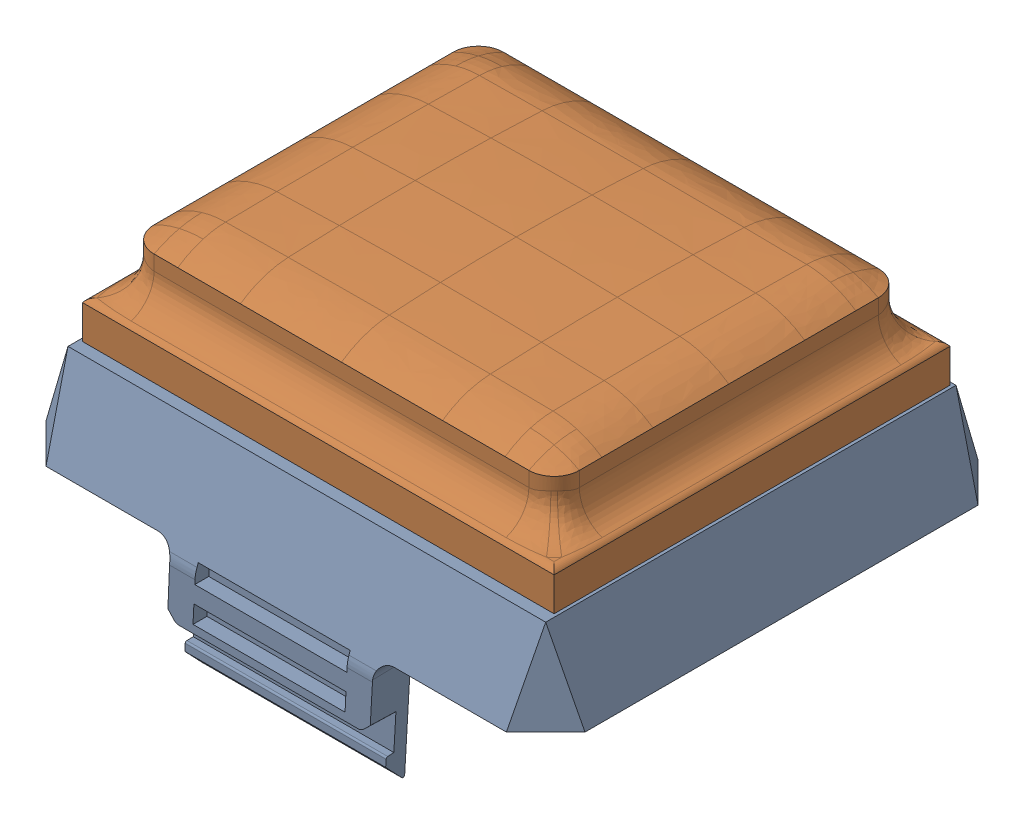
SolidWorks assembly ContiALL2, configuration 默认. Lengths in mm.
Overall size (32 17.53 28.9).
7 component instances, 7 part files, 18 mates.
Components (placement in the parent):
- 3Con1612611Support-1: 3Con1612611Support [默认] at origin size (32 12.05 28.9)
- 3Con1612611OriginalSkin_TOP-1: 3Con1612611OriginalSkin_TOP [默认] at (0 2 0) size (28.02 6.25 23.52) (hidden)
- 3Con1612611Lens-1: 3Con1612611Lens [默认] at (-1.1243 18 1.5226) x (1 0 0) z (0 -1 0) size (24.45 17.04 1)
- 3Con1612611UP-2: 3Con1612611UP [默认] at (0 2 0) size (23.8 4.28 19.29)
- 3Con1612lensside-1: 3Con1612lensside [默认] at origin size (28.33 1.42 23.83)
- 3Con1612downskinnew-1: 3Con1612downskinnew [默认] at origin size (23.65 2.2 19.15)
- continuous-1: continuous [默认] at (-9.5635 23.6 -8.5378) x (1 0 0) z (0 -1 0) size (19.5 16.5 0.4)
Mates (geometry in assembly coordinates):
- 重合1: coordinate: point of Support-1
- 重合8: coincident anti-aligned: plane of Support-1 through (-12.1625 18 0) normal (0.996195 0.087156 0); plane of 611Lens-1 through (-12.075 17 -10.5174) normal (-0.996195 -0.087156 0)
- 重合9: coincident anti-aligned: plane of 611OriginalSkin_TOP-1 through (-0.25 24 9.075) normal (0 0 -1); plane of 3Con1612611UP-2 through (-0.25 24 9.075) normal (0 0 1)
- 重合10: coincident anti-aligned: plane of 611OriginalSkin_TOP-1 through (11.575 24 8.375) normal (-1 0 0); plane of 3Con1612611UP-2 through (11.575 24 8.375) normal (1 0 0)
- 重合11: coincident anti-aligned: plane of 611Support-1 through (-13.75 19 11.5) normal (0 -0.34202 -0.939693); plane of lensside-1 through (-13.75 19 11.5) normal (0 0.34202 0.939693)
- 重合12: coincident anti-aligned: plane of 611Support-1 through (-13.75 19 12.7803) normal (0.939693 -0.34202 0); plane of lensside-1 through (-13.75 19 -11.5) normal (-0.939693 0.34202 0)
- 重合14: coincident anti-aligned: plane of 611Lens-1 through (-1.1243 18 1.5226) normal (0 1 0); plane of lensside-1 through (0 18 0) normal (0 -1 0)
- 重合15: coincident anti-aligned: plane of 611Lens-1 through (-1.1243 18 1.5226) normal (0 1 0); plane of downskinnew-1 through (0 18 0) normal (0 -1 0)
- 重合16: coincident anti-aligned: plane of lensside-1 through (-12.075 17.7531 -9.375) normal (1 0 0); plane of downskinnew-1 through (-12.075 17.7531 -9.375) normal (-1 0 0)
- 重合17: coincident anti-aligned: plane of 611OriginalSkin_TOP-1 through (-0.25 24 9.075) normal (0 0 -1); plane of downskinnew-1 through (-11.375 17.7531 9.075) normal (0 0 1)
- 重合18: coincident anti-aligned: plane of lensside-1 through (-11.375 17.7531 9.075) normal (0 0 -1); plane of downskinnew-1 through (-11.375 17.7531 9.075) normal (0 0 1)
- 重合19: coincident anti-aligned: plane of 3Con1612611UP-2 through (-11.375 20.2 -9.375) normal (0 -1 0); plane of downskinnew-1 through (0 20.2 0) normal (0 1 0)
- 重合20: coincident aligned: plane of 3Con1612611UP-2 through (11.575 24 8.375) normal (1 0 0); plane of downskinnew-1 through (11.575 17.7531 -9.375) normal (1 0 0)
- 重合21: coincident anti-aligned: plane of 611OriginalSkin_TOP-1 through (0 19 0) normal (0 -1 0); plane of lensside-1 through (0 19 0) normal (0 1 0)
- 平行1: parallel: plane of 3Con1612611Lens-1 through (-1.1243 17 1.5226) normal (0 -1 0); plane of continuous-1 through (-9.5635 23.2 -30.7243) normal (0 -1 0)
- 平行2: parallel: plane of 3Con1612611UP-2 through (-12.075 24 8.375) normal (-1 0 0); line of continuous-1 through (-11.0635 23.2 -14.2243) axis (0 0 -1)
- 重合23: coincident: line of 3Con1612611UP-2 through (-8.0635 23.6 -4.0378) axis (0 0 1); line of continuous-1 through (-8.0635 23.6 -24.7243) axis (0 0 -1)
- 重合24: coincident anti-aligned: line of 3Con1612611UP-2 through (-8.0635 23.6 6.4622) axis (-1 0 0); line of continuous-1 through (-9.5635 23.6 -15.7243) axis (1 0 0)
